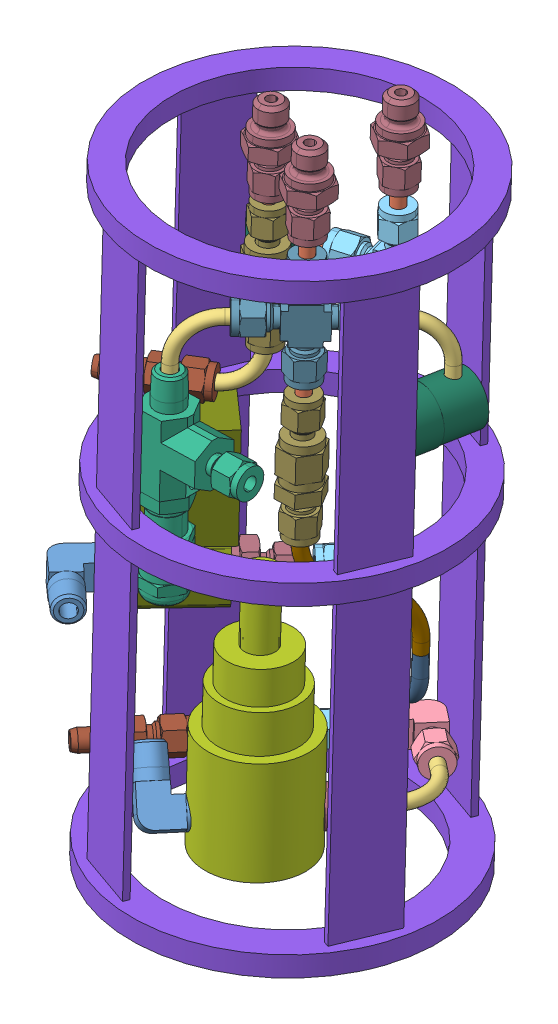
SolidWorks assembly 132000_Pressurant_Bay_Plumbing, configuration 132000_Pressurant_Bay_Plumbing. Lengths in mm.
Overall size (196.95 323.2 205.69).
39 component instances, 16 part files, 39 mates.
Components (placement in the parent):
- 132007_SS-4-ME_raccord_L_NPT-1: 132007_SS-4-ME_raccord_L_NPT [Défaut] at (-5.9888 -1424.5759 483.2154) x (-0.664276 0.022565 0.747147) z (-0.747342 -0.000323 -0.66444) size (33.53 13.72 33.53)
- 132103_tuyau_droit-17: 132103_tuyau_droit [Défaut] at (51.0243 -1504.8847 404.6239) x (0.621944 -0.024043 -0.782692) z (0.483638 -0.774308 0.408095) size (30 6.35 6.35)
- 132101_tuyau_90deg-1: 132101_tuyau_90deg [Défaut] at (69.8907 -1502.8634 433.5637) x (-0.782596 -0.05355 -0.620223) z (0.027001 -0.998276 0.052121) size (52.38 52.38 6.35)
- 132002_SS-400-9_raccord_L_4-4: 132002_SS-400-9_raccord_L_4 [Défaut] at (77.2162 -1503.6409 414.8778) x (-0.782596 -0.05355 -0.620223) z (0.621944 -0.024043 -0.782692) size (35.14 14.22 35.14)
- 132006_raccord_T_4_SS-400-3-7: 132006_raccord_T_4_SS-400-3 [Défaut] at (4.7587 -1503.0962 462.8473) x (0.621944 -0.024043 -0.782692) z (-0.027001 0.998276 -0.052121) size (53.85 14.22 35.14)
- SS-4R3A1-SwagelokCompany-3D-11-18-2022.stp-1: SS-4R3A1-SwagelokCompany-3D-11-18-2022.stp [Défaut] at (20.8748 -1349.2133 495.0492) x (0.99971 0.004641 -0.023651) z (0.005468 -0.999371 0.035044) size (51.64 20.24 98.81)
- 132202_Détendeur-2: 132202_Détendeur [Défaut] at (54.3167 -1515.6397 484.6096) x (-0.783042 -0.026076 -0.621422) z (-0.005468 0.999371 -0.035044) size (50 50 118.8)
- 132103_tuyau_droit-18: 132103_tuyau_droit [Défaut] at (53.5338 -1254.3707 456.7817) x (-0.005468 0.999371 -0.035044) z (0.996345 0.002458 -0.085384) size (30 6.35 6.35)
- 132300_pressurant_bay_mockup-1: 132300_pressurant_bay_mockup [Défaut] at (42.3713 -1541.59 458.7378) x (0.341839 -0.031065 -0.939245) z (0.939743 0.017116 0.341454) size (152.4 300 152.4)
- 132105_tuyau_S_2-1: 132105_tuyau_S_2 [Défaut] at (81.724 -1439.9913 427.6565) x (-0.606708 0.024542 0.794546) z (-0.794906 -0.025607 -0.606192) size (51.2 56 6.4)
- 132103_tuyau_droit-19: 132103_tuyau_droit [Défaut] at (23.9076 -1249.8969 446.5966) x (-0.005468 0.999371 -0.035044) z (0.001495 0.035053 0.999384) size (30 6.35 6.35)
- 132103_tuyau_droit-20: 132103_tuyau_droit [Défaut] at (53.6139 -1385.1345 414.4675) x (-0.005468 0.999371 -0.035044) z (-0.041186 -0.03524 -0.99853) size (30 6.35 6.35)
- 132101_tuyau_90deg-2: 132101_tuyau_90deg [Défaut] at (8.2233 -1328.2973 459.7898) x (-0.839316 0.014464 0.543451) z (0.543616 0.032385 0.838709) size (52.38 52.38 6.35)
- 132101_tuyau_90deg-3: 132101_tuyau_90deg [Défaut] at (77.4692 -1317.3296 434.1444) x (-0.688847 0.021639 0.724584) z (-0.724886 -0.028102 -0.688295) size (52.38 52.38 6.35)
- 132101_tuyau_90deg-4: 132101_tuyau_90deg [Défaut] at (33.9165 -1315.9615 479.9566) x (0.688847 -0.021639 -0.724584) z (0.724886 0.028102 0.688295) size (52.38 52.38 6.35)
- 132103_tuyau_droit-21: 132103_tuyau_droit [Défaut] at (35.2625 -1299.2564 416.8506) x (0.957419 -0.004883 -0.28866) z (-0.209798 -0.698629 -0.684034) size (30 6.35 6.35)
- 132103_tuyau_droit-22: 132103_tuyau_droit [Défaut] at (53.8933 -1320.0663 459.0854) x (-0.005468 0.999371 -0.035044) z (0.919834 -0.00872 -0.392211) size (30 6.35 6.35)
- 132103_tuyau_droit-23: 132103_tuyau_droit [Défaut] at (52.9123 -1256.9173 409.9714) x (-0.005468 0.999371 -0.035044) z (-0.001435 0.035037 0.999385) size (30 6.35 6.35)
- 132103_tuyau_droit-24: 132103_tuyau_droit [Défaut] at (53.2195 -1313.0557 411.9399) x (-0.005468 0.999371 -0.035044) z (-0.001435 0.035037 0.999385) size (30 6.35 6.35)
- 132103_tuyau_droit-25: 132103_tuyau_droit [Défaut] at (53.6708 -1279.4072 457.6596) x (-0.005468 0.999371 -0.035044) z (-0.001435 0.035037 0.999385) size (30 6.35 6.35)
- 132102_tuyau_180deg-4: 132102_tuyau_180deg [Défaut] at (67.9059 -1455.8547 422.58) x (-0.926897 -0.018217 -0.374875) z (-0.375277 0.030432 0.926413) size (36.35 28.17 6.35)
- 132010_SS-QF4-S-400_quick_fitting-1: 132010_SS-QF4-S-400_quick_fitting [Défaut] at (3.5148 -1503.0481 464.4127) x (-0.621944 0.024043 0.782692) z (-0.765639 0.191002 -0.61426) size (44.96 14.3 16.5)
- 132103_tuyau_droit-26: 132103_tuyau_droit [Défaut] at (2.9038 -1503.0245 465.1816) x (0.621944 -0.024043 -0.782692) z (0.778247 0.129642 0.61443) size (30 6.35 6.35)
- 132006_raccord_T_4_SS-400-3-8: 132006_raccord_T_4_SS-400-3 [Défaut] at (53.6936 -1399.7012 414.9783) x (0.005468 -0.999371 0.035044) z (0.664276 -0.022565 -0.747147) size (53.85 14.22 35.14)
- 132003_check_valve_SS-CHS4-25-4: 132003_check_valve_SS-CHS4-25 [Défaut] at (53.3079 -1329.2122 412.5065) x (0.005468 -0.999371 0.035044) z (-0.406496 0.029797 0.913167) size (61.72 17.46 20.16)
- 132003_check_valve_SS-CHS4-25-5: 132003_check_valve_SS-CHS4-25 [Défaut] at (53.9483 -1330.1286 459.4382) x (0.005468 -0.999371 0.035044) z (-0.474344 0.028259 0.879886) size (61.72 17.46 20.16)
- 132005_raccord_SW_G_4_SS-400-1-4RP-5: 132005_raccord_SW_G_4_SS-400-1-4RP [Défaut] at (86.8583 -1501.9103 443.0283) x (-0.621944 0.024043 0.782692) z (-0.762062 -0.248509 -0.597917) size (40.39 19.05 22)
- 132005_raccord_SW_G_4_SS-400-1-4RP-6: 132005_raccord_SW_G_4_SS-400-1-4RP [Défaut] at (52.9539 -1264.5053 410.2374) x (-0.005468 0.999371 -0.035044) z (-0.009624 0.03499 0.999341) size (40.39 19.05 22)
- 132003_check_valve_SS-CHS4-25-6: 132003_check_valve_SS-CHS4-25 [Défaut] at (23.9993 -1266.66 447.1844) x (0.005468 -0.999371 0.035044) z (-0.050941 0.034721 0.998098) size (61.72 17.46 20.16)
- 132005_raccord_SW_G_4_SS-400-1-4RP-7: 132005_raccord_SW_G_4_SS-400-1-4RP [Défaut] at (53.5803 -1262.8593 457.0793) x (-0.005468 0.999371 -0.035044) z (-0.009624 0.03499 0.999341) size (40.39 19.05 22)
- 132005_raccord_SW_G_4_SS-400-1-4RP-8: 132005_raccord_SW_G_4_SS-400-1-4RP [Défaut] at (23.9814 -1263.3723 447.0692) x (-0.005468 0.999371 -0.035044) z (-0.009624 0.03499 0.999341) size (40.39 19.05 22)
- 132009_SS-400-4_raccord_X_Sw-1: 132009_SS-400-4_raccord_X_Sw [Défaut] at (53.622 -1270.4935 457.347) x (0.005468 -0.999371 0.035044) z (-0.688847 0.021639 0.724584) size (53.85 14.22 53.85)
- 132005_raccord_SW_G_4_SS-400-1-4RP-9: 132005_raccord_SW_G_4_SS-400-1-4RP [Défaut] at (34.6274 -1425.9556 437.5323) x (-0.664276 0.022565 0.747147) z (-0.747318 0.001243 -0.664466) size (40.39 19.05 22)
- 132201_AG2029_soleno_8-3: 132201_AG2029_soleno_8 [Défaut] at (7.8334 -1292.1714 424.8654) x (-0.288649 -0.03513 -0.95679) z (-0.957419 0.004883 0.28866) size (26.06 49.78 26.06)
- 132201_AG2029_soleno_8-4: 132201_AG2029_soleno_8 [Défaut] at (91.8254 -1335.6773 413.9741) x (-0.988898 -0.010608 -0.148214) z (-0.005468 0.999371 -0.035044) size (26.06 49.78 26.06)
- 132203_soleno_quart-2: 132203_soleno_quart [Défaut] at (-72.2403 -1443.0744 441.3396) x (-0.747467 -0.027365 -0.663735) z (0.664276 -0.022565 -0.747147) size (28 80.02 47.02)
- 132010_SS-QF4-S-400_quick_fitting-2: 132010_SS-QF4-S-400_quick_fitting [Défaut] at (9.7207 -1347.5092 459.5611) x (-0.839316 0.014464 0.543451) z (-0.542446 -0.088602 -0.835406) size (44.96 14.3 16.5)
- 132006_raccord_T_4_SS-400-3-9: 132006_raccord_T_4_SS-400-3 [Défaut] at (52.9973 -1272.4405 410.5157) x (0.005468 -0.999371 0.035044) z (0.957419 -0.004883 -0.28866) size (53.85 14.22 35.14)
- 132007_SS-4-ME_raccord_L_NPT-2: 132007_SS-4-ME_raccord_L_NPT [Défaut] at (18.0624 -1479.3333 502.0496) x (0.49179 -0.765825 0.414312) z (-0.621944 0.024043 0.782692) size (33.53 13.72 33.53)
Mates (geometry in assembly coordinates):
- Coaxiale1: concentric anti-aligned: cylinder of 132101_tuyau_90deg-4 through (54.4769 -1297.4227 457.5462) axis (-0.688847 0.021639 0.724584) radius 3.175; cylinder of 132009_SS-400-4_raccord_X_Sw-1 through (40.4718 -1296.9828 472.2779) axis (0.688847 -0.021639 -0.724584) radius 3.175
- Coaxiale2: concentric aligned: cylinder of 132103_tuyau_droit-24 through (53.3885 -1343.9383 413.0229) axis (-0.005468 0.999371 -0.035044) radius 3.175; cylinder of 132003_check_valve_SS-CHS4-25-4 through (53.6038 -1383.2801 414.4024) axis (-0.005468 0.999371 -0.035044) radius 3.175
- Coaxiale3: concentric aligned: cylinder of 132101_tuyau_90deg-2 through (-16.8512 -1347.0513 476.7662) axis (0.839316 -0.014464 -0.543451) radius 3.175; cylinder of 132010_SS-QF4-S-400_quick_fitting-2 through (-19.6991 -1347.0022 478.6101) axis (0.839316 -0.014464 -0.543451) radius 3.048
- Coaxiale4: concentric anti-aligned: cylinder of 132103_tuyau_droit-22 through (54.0623 -1350.9488 460.1683) axis (-0.005468 0.999371 -0.035044) radius 3.175; cylinder of 132003_check_valve_SS-CHS4-25-5 through (53.99 -1337.7438 459.7053) axis (0.005468 -0.999371 0.035044) radius 3.175
- Coaxiale5: concentric anti-aligned: cylinder of 132202_Détendeur-2 through (71.3381 -1501.3103 462.5599) axis (-0.621944 0.024043 0.782692) radius 6.35; cylinder of 132005_raccord_SW_G_4_SS-400-1-4RP-5 through (64.7518 -1501.0557 470.8486) axis (0.621944 -0.024043 -0.782692) radius 6.5785
- Distance1: distance = 0 mm anti-aligned: plane of 132102_tuyau_180deg-4 through (81.7546 -1445.5878 427.8527) normal (-0.005468 0.999371 -0.035044); plane of 132105_tuyau_S_2-1 through (81.7546 -1445.5878 427.8527) normal (0.005468 -0.999371 0.035044)
- Coaxiale6: concentric anti-aligned: cylinder of 132105_tuyau_S_2-1 through (81.7546 -1445.5878 427.8527) axis (-0.005468 0.999371 -0.035044) radius 3.2; cylinder of 132102_tuyau_180deg-4 through (81.7546 -1445.5878 427.8527) axis (0.005468 -0.999371 0.035044) radius 3.175
- Coaxiale7: concentric aligned: cylinder of 132101_tuyau_90deg-3 through (90.6951 -1317.7451 420.2324) axis (0.005468 -0.999371 0.035044) radius 3.175; cone of 132201_AG2029_soleno_8-4 through (90.7234 -1322.9146 420.4137) axis (0.005468 -0.999371 0.035044)
- Coaxiale8: concentric anti-aligned: cylinder of SS-4R3A1-SwagelokCompany-3D-11-18-2022.stp-1 through (20.7508 -1326.553 494.2546) axis (-0.005468 0.999371 -0.035044) radius 3.556; cylinder of 132101_tuyau_90deg-4 through (20.6906 -1315.546 493.8686) axis (0.005468 -0.999371 0.035044) radius 3.175
- Coaxiale9: concentric aligned: cylinder of 132103_tuyau_droit-17 through (31.805 -1504.1417 428.8106) axis (0.621944 -0.024043 -0.782692) radius 3.175; cylinder of 132006_raccord_T_4_SS-400-3-7 through (9.4979 -1503.2794 456.8832) axis (0.621944 -0.024043 -0.782692) radius 3.175
- Coaxiale10: concentric aligned: cylinder of 132103_tuyau_droit-17 through (31.805 -1504.1417 428.8106) axis (0.621944 -0.024043 -0.782692) radius 3.175; cylinder of 132002_SS-400-9_raccord_L_4-4 through (44.1395 -1504.6185 413.288) axis (0.621944 -0.024043 -0.782692) radius 3.175
- Coaxiale11: concentric anti-aligned: cylinder of 132103_tuyau_droit-19 through (24.0766 -1280.7795 447.6796) axis (-0.005468 0.999371 -0.035044) radius 3.175; cylinder of 132003_check_valve_SS-CHS4-25-6 through (24.041 -1274.2752 447.4515) axis (0.005468 -0.999371 0.035044) radius 3.175
- Coaxiale12: concentric aligned: cylinder of 132103_tuyau_droit-23 through (53.0813 -1287.7998 411.0543) axis (-0.005468 0.999371 -0.035044) radius 3.175; cylinder of 132005_raccord_SW_G_4_SS-400-1-4RP-6 through (52.9122 -1256.8901 409.9704) axis (-0.005468 0.999371 -0.035044) radius 3.175
- Coaxiale13: concentric aligned: cylinder of 132103_tuyau_droit-19 through (24.0766 -1280.7795 447.6796) axis (-0.005468 0.999371 -0.035044) radius 3.175; cylinder of 132005_raccord_SW_G_4_SS-400-1-4RP-8 through (23.9397 -1255.7571 446.8021) axis (-0.005468 0.999371 -0.035044) radius 3.175
- Coaxiale14: concentric aligned: cylinder of 132103_tuyau_droit-18 through (53.7028 -1285.2533 457.8646) axis (-0.005468 0.999371 -0.035044) radius 3.175; cylinder of 132005_raccord_SW_G_4_SS-400-1-4RP-7 through (53.5386 -1255.2441 456.8123) axis (-0.005468 0.999371 -0.035044) radius 3.175
- Coïncidente1: coincident anti-aligned: plane of 132005_raccord_SW_G_4_SS-400-1-4RP-9 through (15.73 -1425.3136 458.7871) normal (-0.664276 0.022565 0.747147); plane of 132203_soleno_quart-2 through (-42.3479 -1444.0898 407.718) normal (0.664276 -0.022565 -0.747147)
- Coaxiale15: concentric anti-aligned: cylinder of 132103_tuyau_droit-23 through (53.0813 -1287.7998 411.0543) axis (-0.005468 0.999371 -0.035044) radius 3.175; cylinder of 132006_raccord_T_4_SS-400-3-9 through (53.039 -1280.0557 410.7827) axis (0.005468 -0.999371 0.035044) radius 3.175
- Coaxiale16: concentric anti-aligned: cylinder of 132202_Détendeur-2 through (71.3381 -1501.3103 462.5599) axis (-0.621944 0.024043 0.782692) radius 6.35; cylinder of 132007_SS-4-ME_raccord_L_NPT-2 through (43.0692 -1500.2175 498.1353) axis (0.621944 -0.024043 -0.782692) radius 3.556
- Coaxiale17: concentric aligned: cylinder of 132103_tuyau_droit-21 through (5.6763 -1299.1055 425.7708) axis (0.957419 -0.004883 -0.28866) radius 3.175; cylinder of 132006_raccord_T_4_SS-400-3-9 through (34.6625 -1299.2533 417.0315) axis (0.957419 -0.004883 -0.28866) radius 3.175
- Coaxiale18: concentric aligned: cylinder of 132101_tuyau_90deg-2 through (24.3381 -1328.575 449.3556) axis (-0.005468 0.999371 -0.035044) radius 3.175; cylinder of 132003_check_valve_SS-CHS4-25-6 through (24.2952 -1320.728 449.0804) axis (-0.005468 0.999371 -0.035044) radius 3.175
- Parallèle1: parallel aligned: plane of 132002_SS-400-9_raccord_L_4-4 through (48.3325 -1505.3128 397.819) normal (-0.782596 -0.05355 -0.620223); plane of 132006_raccord_T_4_SS-400-3-7 through (10.6759 -1497.5246 444.6616) normal (-0.782596 -0.05355 -0.620223)
- Parallèle2: parallel anti-aligned: cylinder of 132103_tuyau_droit-18 through (53.7028 -1285.2533 457.8646) axis (-0.005468 0.999371 -0.035044) radius 3.175; cylinder of 132101_tuyau_90deg-3 through (90.6951 -1317.7451 420.2324) axis (0.005468 -0.999371 0.035044) radius 3.175
- Parallèle3: parallel aligned: cylinder of 132202_Détendeur-2 through (54.0367 -1464.4719 482.8153) axis (0.005468 -0.999371 0.035044) radius 25; line of 132300_pressurant_bay_mockup-1 through (4.3533 -1379.853 511.333) axis (0.005468 -0.999371 0.035044)
- Parallèle4: parallel aligned: cylinder of 132103_tuyau_droit-18 through (53.7028 -1285.2533 457.8646) axis (-0.005468 0.999371 -0.035044) radius 3.175; cylinder of 132103_tuyau_droit-19 through (24.0766 -1280.7795 447.6796) axis (-0.005468 0.999371 -0.035044) radius 3.175
- Parallèle5: parallel aligned: cylinder of 132103_tuyau_droit-24 through (53.3885 -1343.9383 413.0229) axis (-0.005468 0.999371 -0.035044) radius 3.175; cylinder of 132201_AG2029_soleno_8-3 through (8.0778 -1336.8433 426.4319) axis (-0.005468 0.999371 -0.035044) radius 13.03
- Coaxiale19: concentric aligned: cylinder of 132103_tuyau_droit-22 through (54.0623 -1350.9488 460.1683) axis (-0.005468 0.999371 -0.035044) radius 3.175; cylinder of 132103_tuyau_droit-25 through (53.8398 -1310.2897 458.7426) axis (-0.005468 0.999371 -0.035044) radius 3.175
- Coaxiale20: concentric aligned: cylinder of 132105_tuyau_S_2-1 through (54.2985 -1394.12 461.6822) axis (-0.005468 0.999371 -0.035044) radius 3.2; cylinder of 132003_check_valve_SS-CHS4-25-5 through (54.2442 -1384.1965 461.3342) axis (-0.005468 0.999371 -0.035044) radius 3.175
- Coaxiale21: concentric aligned: cylinder of 132103_tuyau_droit-18 through (53.7028 -1285.2533 457.8646) axis (-0.005468 0.999371 -0.035044) radius 3.175; cylinder of 132103_tuyau_droit-25 through (53.8398 -1310.2897 458.7426) axis (-0.005468 0.999371 -0.035044) radius 3.175
- Coïncidente2: coincident aligned: plane of 132005_raccord_SW_G_4_SS-400-1-4RP-6 through (52.7564 -1224.2299 406.3905) normal (-0.005468 0.999371 -0.035044); plane of 132005_raccord_SW_G_4_SS-400-1-4RP-8 through (23.7839 -1223.0968 443.2222) normal (-0.005468 0.999371 -0.035044)
- Coïncidente3: coincident aligned: plane of 132005_raccord_SW_G_4_SS-400-1-4RP-7 through (53.3828 -1222.5839 453.2324) normal (-0.005468 0.999371 -0.035044); plane of 132005_raccord_SW_G_4_SS-400-1-4RP-8 through (23.7839 -1223.0968 443.2222) normal (-0.005468 0.999371 -0.035044)
- Distance2: distance = 2 mm anti-aligned: plane of 132010_SS-QF4-S-400_quick_fitting-1 through (0.7922 -1502.3689 462.2283) normal (0.621944 -0.024043 -0.782692); plane of 132006_raccord_T_4_SS-400-3-7 through (4.6627 -1499.5463 462.6619) normal (-0.621944 0.024043 0.782692)
- Coaxiale22: concentric aligned: cylinder of 132006_raccord_T_4_SS-400-3-7 through (9.4979 -1503.2794 456.8832) axis (0.621944 -0.024043 -0.782692) radius 3.175; cylinder of 132103_tuyau_droit-26 through (-16.3156 -1502.2815 489.3684) axis (0.621944 -0.024043 -0.782692) radius 3.175
- Coaxiale23: concentric aligned: cylinder of 132010_SS-QF4-S-400_quick_fitting-1 through (-18.2856 -1502.2053 491.8476) axis (0.621944 -0.024043 -0.782692) radius 3.048; axis of 132103_tuyau_droit-26 through (-16.3156 -1502.2815 489.3684) axis (0.621944 -0.024043 -0.782692)
- Coaxiale24: concentric aligned: cylinder of 132101_tuyau_90deg-1 through (84.9166 -1501.8352 445.472) axis (-0.621944 0.024043 0.782692) radius 3.175; cylinder of 132005_raccord_SW_G_4_SS-400-1-4RP-5 through (82.1191 -1501.7271 448.9925) axis (-0.621944 0.024043 0.782692) radius 3.175
- Coaxiale25: concentric anti-aligned: cylinder of 132007_SS-4-ME_raccord_L_NPT-1 through (-11.005 -1424.4055 488.8574) axis (0.664276 -0.022565 -0.747147) radius 3.556; cylinder of 132203_soleno_quart-2 through (-14.1624 -1424.2982 492.4087) axis (-0.664276 0.022565 0.747147) radius 3.3782
- Coaxiale26: concentric aligned: cylinder of 132102_tuyau_180deg-4 through (54.0024 -1456.128 416.9569) axis (-0.005468 0.999371 -0.035044) radius 3.175; cylinder of 132006_raccord_T_4_SS-400-3-8 through (53.9464 -1445.9001 416.5983) axis (-0.005468 0.999371 -0.035044) radius 3.175
- Coaxiale27: concentric anti-aligned: cylinder of 132101_tuyau_90deg-1 through (58.3542 -1504.9315 399.9293) axis (0.782596 0.05355 0.620223) radius 3.175; cylinder of 132002_SS-400-9_raccord_L_4-4 through (71.2528 -1504.0489 410.1517) axis (-0.782596 -0.05355 -0.620223) radius 3.175
- Coaxiale28: concentric anti-aligned: cylinder of 132005_raccord_SW_G_4_SS-400-1-4RP-9 through (11.0161 -1425.1535 464.0891) axis (0.664276 -0.022565 -0.747147) radius 6.5785; cylinder of 132203_soleno_quart-2 through (-14.1624 -1424.2982 492.4087) axis (-0.664276 0.022565 0.747147) radius 3.3782
- Coaxiale29: concentric anti-aligned: cylinder of 132103_tuyau_droit-25 through (53.8398 -1310.2897 458.7426) axis (-0.005468 0.999371 -0.035044) radius 3.175; cylinder of 132009_SS-400-4_raccord_X_Sw-1 through (53.6637 -1278.1087 457.6141) axis (0.005468 -0.999371 0.035044) radius 3.175
